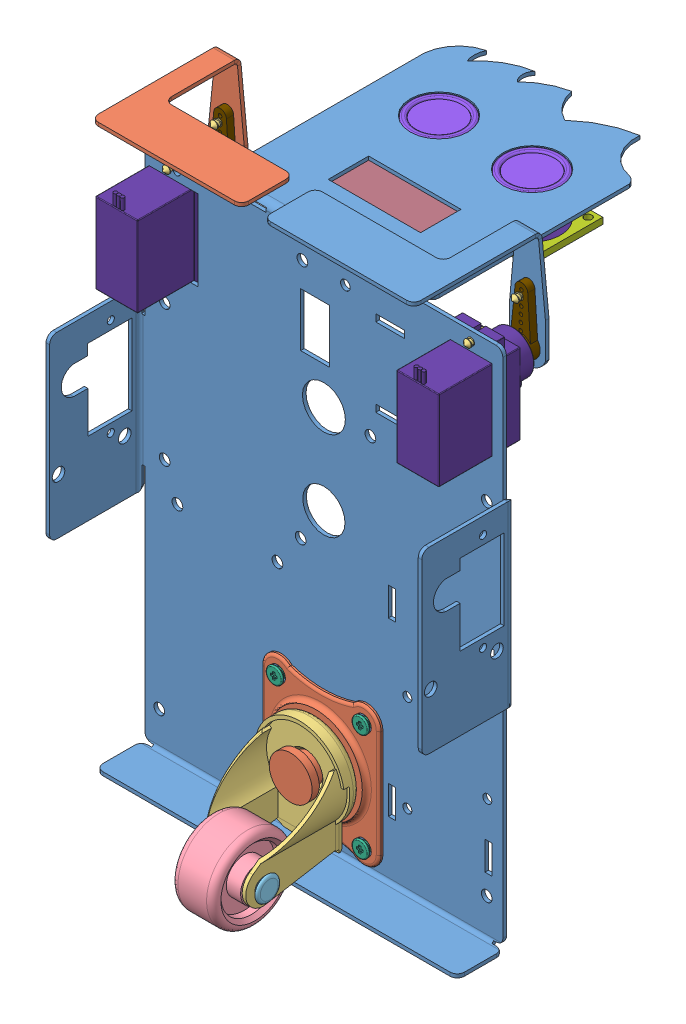
SolidWorks assembly MS_OL_PU, configuration Predeterminado. Lengths in mm.
Overall size (105.01 167.87 107.11).
59 component instances, 22 part files, 12 mates.
Components (placement in the parent):
- DYOR_OLED_MetalSheet_Pusher-1: DYOR_OLED_MetalSheet_Pusher [Predeterminado] at (90.3983 -137.9363 139.7994) size (105.01 148.39 94.67)
- CA-1: CA [Predeterminado] at (2.8546 -16.6172 1.124) size (33 45.94 42.59)
  - Caster Wheel-1: Caster Wheel [Default] at (194.2283 -297.83 183.8938) x (0 1 0) z (-1 0 0) size (45.94 37.59 33)
    - caster holder-1: caster holder [Default] at (-24.0751 44.7184 29.5137) x (1 0 0) z (0 0 -1) size (39 9.27 33)
    - holder-1: holder [Default] at (-1.5751 42.9484 46.0137) x (0 0 1) z (1 0 0) size (25 28.07 31.31)
    - caster wheel-1: caster wheel [Default] at (-15.6961 19.9484 46.0137) x (0.997275 0.073773 0) z (0 0 1) size (23 23 14)
    - Part4-1: Part4 [Default] at (-15.6961 19.9484 55.0137) x (-0.978448 0.206495 0) z (0 0 -1) size (7 7 20)
  - M3x6 SelfTap Screw-1: M3x6 SelfTap Screw [Predeterminado] at (136.2146 -284.4051 140.6754) size (4.62 4.62 7)
  - M3x6 SelfTap Screw-2: M3x6 SelfTap Screw [Predeterminado] at (136.2146 -314.4051 140.6754) size (4.62 4.62 7)
  - M3x6 SelfTap Screw-3: M3x6 SelfTap Screw [Predeterminado] at (160.2146 -284.4051 140.6754) size (4.62 4.62 7)
  - M3x6 SelfTap Screw-4: M3x6 SelfTap Screw [Predeterminado] at (160.2146 -314.4051 140.6754) size (4.62 4.62 7)
- HC-SR04 Ping Sensor-1: HC-SR04 Ping Sensor [Default] at (151.0973 -203.2073 94.6556) x (0 0 -1) z (0 1 0) size (25.18 45 18.07)
  - PCB-1: PCB [Default] at origin size (20.5 45 1.75)
  - Transducer-1: Transducer [Default] at (0 -13 13.25) x (1 0 0) z (0 -1 0) size (15.88 12 15.88)
  - Transducer-2: Transducer [Default] at (0 13 13.25) x (1 0 0) z (0 -1 0) size (15.88 12 15.88)
  - 3 Pin Header 90 Degree-1: 3 Pin Header 90 Degree [Default] at (8.4275 0 -1.25) x (-1 0 0) z (0 -1 0) size (8 7.82 10)
  - 14 Pin SMT-1: 14 Pin SMT [Default] at (-0.35 -18.5 -0.85) x (0 -1 0) z (1 0 0) size (6 1.6 8.8)
  - 14 Pin SMT-2: 14 Pin SMT [Default] at (0 -0.3826 -0.85) x (1 0 0) z (0 1 0) size (6 1.6 8.8)
  - 14 Pin SMT-3: 14 Pin SMT [Default] at (0 17.5274 -0.85) x (1 0 0) z (0 1 0) size (6 1.6 8.8)
  - Cap1 SMT-1: Cap1 SMT [Default] at (-1.755 7.4774 -0.9689) x (0 1 0) z (-1 0 0) size (4.5 1.84 1.75)
  - Cap1 SMT-2: Cap1 SMT [Default] at (6.835 7.4774 -0.9689) x (0 1 0) z (-1 0 0) size (4.5 1.84 1.75)
  - Cap1 SMT-3: Cap1 SMT [Default] at (-6.835 7.4774 -0.9689) x (0 1 0) z (-1 0 0) size (4.5 1.84 1.75)
  - Cap1 SMT-4: Cap1 SMT [Default] at (4.295 7.4774 -0.9689) x (0 1 0) z (-1 0 0) size (4.5 1.84 1.75)
  - Cap1 SMT-5: Cap1 SMT [Default] at (1.755 7.4774 -0.9689) x (0 1 0) z (-1 0 0) size (4.5 1.84 1.75)
  - Cap1 SMT-6: Cap1 SMT [Default] at (-4.295 7.4774 -0.9689) x (0 1 0) z (-1 0 0) size (4.5 1.84 1.75)
  - HC-SR04 Crystal-1: HC-SR04 Crystal [Default] at (-8.3 0 1.75) x (0 -1 0) z (0 0 1) size (10 3.5 2.7)
- OLED_0.91_128x32-1: OLED_0.91_128x32 [Predeterminado] at (152.1882 -192.9673 119.9615) x (1 0 0) z (0 1 0) size (38.3 12.1 11.46)
  - OLED_0.91_128x32.stp-1: OLED_0.91_128x32.stp [Predeterminado] at origin size (38.3 12.1 11.46)
    - OLED_0.91_128x32.stp-1: OLED_0.91_128x32.stp [Predeterminado] at origin size (38.3 12.1 2.57)
    - Pin Header 4 x 1 TH 2.54mm Pitch.stp-1: Pin Header 4 x 1 TH 2.54mm Pitch.stp [Predeterminado] at (-17.55 -3.81 -2.6) size (2.54 10.16 11.43)
    - RESC-0603.stp-1: RESC-0603.stp [Predeterminado] at (4.3 -5.3 0) x (1 0 0) z (0 0 -1) size (1.7 0.9 0.55)
    - RESC-0603.stp-2: RESC-0603.stp [Predeterminado] at (4.3 -3.8 0) x (1 0 0) z (0 0 -1) size (1.7 0.9 0.55)
    - RESC-0603.stp-3: RESC-0603.stp [Predeterminado] at (4.3 -2.3 0) x (1 0 0) z (0 0 -1) size (1.7 0.9 0.55)
    - RESC-0603.stp-4: RESC-0603.stp [Predeterminado] at (4.3 -0.8 0) x (1 0 0) z (0 0 -1) size (1.7 0.9 0.55)
    - RESC-0603.stp-5: RESC-0603.stp [Predeterminado] at (4.3 0.7 0) x (1 0 0) z (0 0 -1) size (1.7 0.9 0.55)
    - RESC-0603.stp-6: RESC-0603.stp [Predeterminado] at (4.3 2.2 0) x (1 0 0) z (0 0 -1) size (1.7 0.9 0.55)
    - RESC-0603.stp-7: RESC-0603.stp [Predeterminado] at (4.3 3.7 0) x (1 0 0) z (0 0 -1) size (1.7 0.9 0.55)
    - RESC-0603.stp-8: RESC-0603.stp [Predeterminado] at (4.3 5.2 0) x (1 0 0) z (0 0 -1) size (1.7 0.9 0.55)
    - RESC-0603.stp-9: RESC-0603.stp [Predeterminado] at (-1.4 -3.06 0) x (1 0 0) z (0 0 -1) size (1.7 0.9 0.55)
    - RESC-0603.stp-10: RESC-0603.stp [Predeterminado] at (-1.4 -1.56 0) x (1 0 0) z (0 0 -1) size (1.7 0.9 0.55)
    - RESC-0603.stp-11: RESC-0603.stp [Predeterminado] at (-1.4 -0.06 0) x (1 0 0) z (0 0 -1) size (1.7 0.9 0.55)
    - RESC-0603.stp-12: RESC-0603.stp [Predeterminado] at (-1.4 1.44 0) x (1 0 0) z (0 0 -1) size (1.7 0.9 0.55)
    - RESC-0603.stp-13: RESC-0603.stp [Predeterminado] at (-1.4 2.94 0) x (1 0 0) z (0 0 -1) size (1.7 0.9 0.55)
    - 2SD0601A.stp-1: 2SD0601A.stp [Predeterminado] at (-9.8 -1.3 -0.08) x (1 0 0) z (0 1 0) size (2.76 1.18 2.9)
- PU-1: PU [Predeterminado] at (-15.3265 -30.2219 -1.0225) size (95.94 49.57 37.38)
  - sg90-1: sg90 [Default] at (201.5956 -166.7354 155.7219) x (0 -1 0) z (1 0 0) size (31.9 29.9 11.8)
  - sg90-2: sg90 [Default] at (117.452 -166.7354 155.7219) x (0 -1 0) z (1 0 0) size (31.9 29.9 11.8)
  - SG90 plastic Horn-1: SG90 plastic Horn [Default] at (123.352 -172.6354 127.0219) x (0.017141 0.999853 0) z (-0.999853 0.017141 0) size (19.4 4 7.07)
  - SG90 plastic Horn-2: SG90 plastic Horn [Default] at (207.4956 -172.6354 127.0219) x (0.020276 0.999794 0) z (-0.999794 0.020276 0) size (19.4 4 7.07)
  - Pusher_left-1: Pusher_left [Predeterminado] at (252.6438 -158.8738 124.0219) x (-1 0 0) z (0 0 -1) size (44 33.65 35.77)
  - Pusher_right-1: Pusher_right [Predeterminado] at (78.2037 -158.8738 125.0219) size (44 33.65 35.77)
  - M2x6 SelfTap Screw-1: M2x6 SelfTap Screw [Predeterminado] at (207.4956 -164.3354 136.8219) x (-0.923728 -0.383049 0) z (0 0 -1) size (3.4 3.28 6)
  - M2x6 SelfTap Screw-2: M2x6 SelfTap Screw [Predeterminado] at (207.4956 -191.6354 136.3219) x (-0.923728 -0.383049 0) z (0 0 -1) size (3.4 3.28 6)
  - M2x6 SelfTap Screw-3: M2x6 SelfTap Screw [Predeterminado] at (123.352 -164.3354 136.8219) x (-0.993348 0.115149 0) z (0 0 -1) size (3.4 3.28 6)
  - M2x6 SelfTap Screw-4: M2x6 SelfTap Screw [Predeterminado] at (123.352 -191.6354 136.8219) x (-0.923728 -0.383049 0) z (0 0 -1) size (3.4 3.28 6)
  - (M2_3_mm)_90116A007_METRIC 316 SS PAN HEAD PHILLIPS MACHINE SCREW-1: (M2_3_mm)_90116A007_METRIC 316 SS PAN HEAD PHILLIPS MACHINE SCREW [90116A007] at (123.352 -172.6354 127.0219) x (-0.923728 -0.383049 0) z (0 0 -1) size (4 4 4.68)
  - (M2_3_mm)_90116A007_METRIC 316 SS PAN HEAD PHILLIPS MACHINE SCREW-2: (M2_3_mm)_90116A007_METRIC 316 SS PAN HEAD PHILLIPS MACHINE SCREW [90116A007] at (207.4956 -172.6354 127.0219) x (-0.923728 -0.383049 0) z (0 0 -1) size (4 4 4.68)
  - M2x6 SelfTap Screw-5: M2x6 SelfTap Screw [Predeterminado] at (123.352 -160.1354 123.5219) x (-0.923728 -0.383049 0) z (0 0 -1) size (3.4 3.28 6)
  - M2x6 SelfTap Screw-6: M2x6 SelfTap Screw [Predeterminado] at (207.4956 -160.1354 123.5219) x (-0.923728 -0.383049 0) z (0 0 -1) size (3.4 3.28 6)
Mates (geometry in assembly coordinates):
- Concéntrica334: concentric: circle of DYOR_OLED_MetalSheet_Pusher-1; circle of ?
- Concéntrica335: concentric: circle of DYOR_OLED_MetalSheet_Pusher-1; circle of ?
- Concéntrica336: concentric: circle of DYOR_OLED_MetalSheet_Pusher-1; circle of HC-SR04 Ping Sensor-1/Transducer-1
- Paralelo106: parallel: plane of DYOR_OLED_MetalSheet_Pusher-1 through (204.0691 -229.071 138.7994) normal (0 0 -1); plane of HC-SR04 Ping Sensor-1/PCB-1 through (128.5973 -201.4573 104.9056) normal (0 0 1)
- Coincidente580: coincident: plane of DYOR_OLED_MetalSheet_Pusher-1 through (204.0691 -189.4573 177.7693) normal (0 1 0); plane of HC-SR04 Ping Sensor-1/Transducer-1 through (164.0973 -189.4573 86.7156) normal (0 1 0)
- Coincidente581: coincident: plane of DYOR_OLED_MetalSheet_Pusher-1 through (204.0691 -190.4573 177.7693) normal (0 -1 0); plane of OLED_0.91_128x32-1/OLED_0.91_128x32.stp-1/OLED_0.91_128x32.stp-1 through (150.9882 -190.4573 119.9615) normal (0 1 0)
- Coincidente584: coincident: plane of DYOR_OLED_MetalSheet_Pusher-1 through (204.0691 -229.071 138.7994) normal (0 0 -1); plane of PU-1/sg90-1 through (198.0691 -224.1573 138.7994) normal (0 0 1)
- Coincidente585: coincident: plane of DYOR_OLED_MetalSheet_Pusher-1 through (204.0691 -229.071 139.7994) normal (0 0 1); plane of CA-1/Caster Wheel-1/caster holder-1 through (151.0691 -271.2241 139.7994) normal (0 0 -1)
- Concéntrica337: concentric: circle of DYOR_OLED_MetalSheet_Pusher-1; circle of PU-1/M2x6 SelfTap Screw-2
- Concéntrica338: concentric: circle of DYOR_OLED_MetalSheet_Pusher-1; circle of CA-1/Caster Wheel-1/caster holder-1
- Coincidente586: coincident: plane of DYOR_OLED_MetalSheet_Pusher-1 through (138.0882 -190.4573 114.3115) normal (1 0 0); plane of OLED_0.91_128x32-1/OLED_0.91_128x32.stp-1/OLED_0.91_128x32.stp-1 through (138.0882 -190.5173 114.3115) normal (-1 0 0)
- Coincidente587: coincident: plane of DYOR_OLED_MetalSheet_Pusher-1 through (163.8882 -190.4573 114.3115) normal (0 0 1); plane of OLED_0.91_128x32-1/OLED_0.91_128x32.stp-1/OLED_0.91_128x32.stp-1 through (163.8882 -190.5173 114.3115) normal (0 0 -1)
